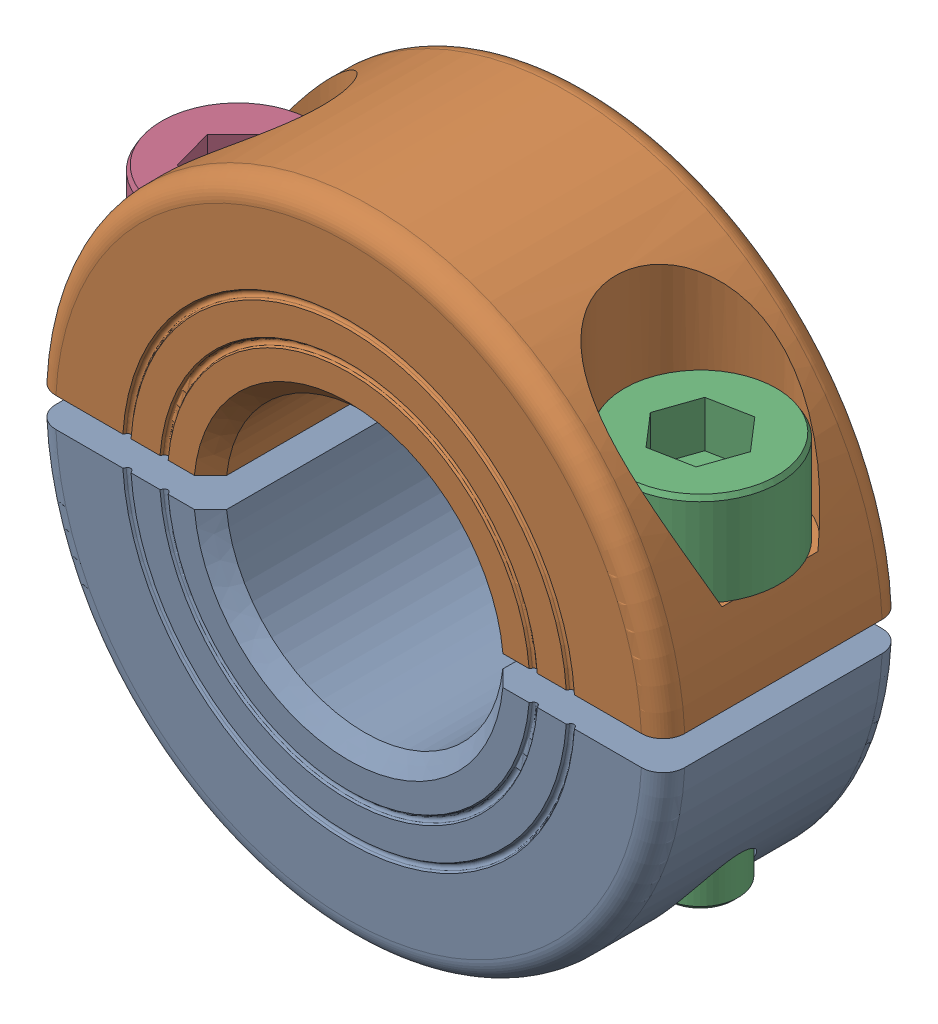
SolidWorks assembly v2Ruland_msp-15-x, configuration Default. Lengths in mm.
Overall size (37 34 13.13).
5 component instances, 3 part files, 4 mates.
Components (placement in the parent):
- v2Ruland_msp series_msp-15-f-1: v2Ruland_msp series_msp-15-f [Default] at (0.2973 -7.1364 21.6972) size (34.1 34 13.13)
  - v2Ruland_msp collars bottom half_msp-15-f-1: v2Ruland_msp collars bottom half_msp-15-f [Default] at origin size (34.1 16.21 13.13)
  - v2Ruland_msp collars top half_msp-15-f-1: v2Ruland_msp collars top half_msp-15-f [Default] at origin size (34.1 16.21 13.13)
- v2Ruland_metric socket head cap screws 1_cfm5_16-1: v2Ruland_metric socket head cap screws 1_cfm5_16 [Default] at (12.7941 -2.1516 28.1972) x (-0.654447 0 -0.756108) z (0 1 0) size (8.5 8.5 21)
- v2Ruland_metric socket head cap screws 1_cfm5_16-2: v2Ruland_metric socket head cap screws 1_cfm5_16 [Default] at (-12.1995 -2.1516 28.1972) x (0.705759 0 -0.708452) z (0 1 0) size (8.5 8.5 21)
Mates (geometry in assembly coordinates):
- Concentric1: concentric anti-aligned: circle of Ruland_msp series_msp-15-f-1/Ruland_msp collars top half_msp-15-f-1; circle of Ruland_metric socket head cap screws 1_cfm5_16-1
- Concentric2: concentric anti-aligned: circle of Ruland_msp series_msp-15-f-1/Ruland_msp collars top half_msp-15-f-1; circle of Ruland_metric socket head cap screws 1_cfm5_16-2
- Coincident1: coincident anti-aligned: plane of Ruland_msp series_msp-15-f-1/Ruland_msp collars top half_msp-15-f-1 through (-12.1995 -2.1516 28.1972) normal (0 1 0); plane of Ruland_metric socket head cap screws 1_cfm5_16-2 through (-12.1995 -2.1516 28.1972) normal (0 -1 0)
- Coincident2: coincident anti-aligned: plane of Ruland_msp series_msp-15-f-1/Ruland_msp collars top half_msp-15-f-1 through (12.7941 -2.1516 28.1972) normal (0 1 0); plane of Ruland_metric socket head cap screws 1_cfm5_16-1 through (12.7941 -2.1516 28.1972) normal (0 -1 0)
